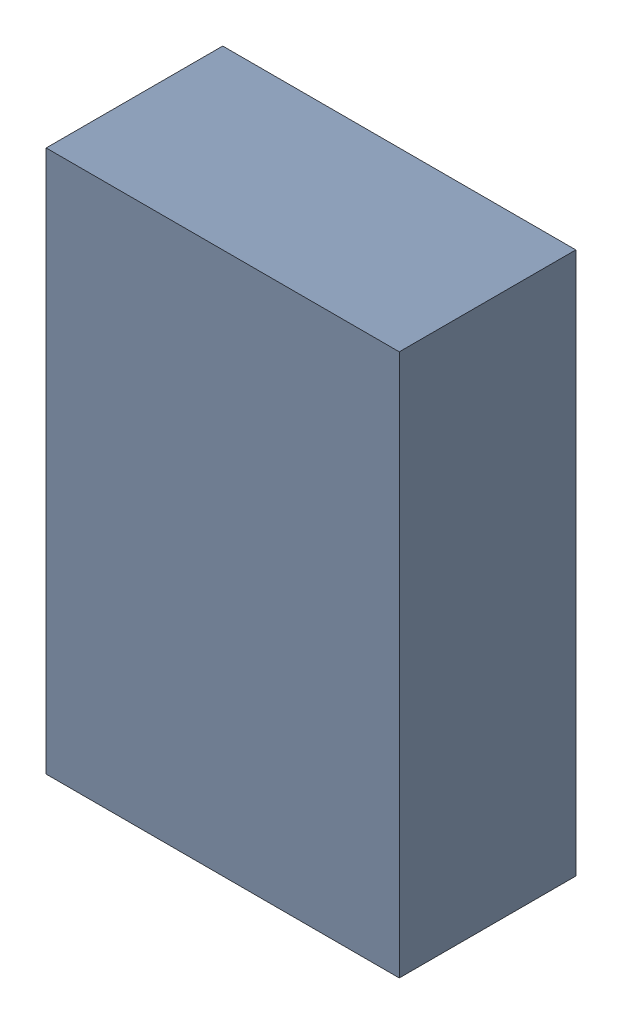
SolidWorks assembly R6-1, configuration Default. Lengths in mm.
Overall size (1.4 2.15 0.7).
2 component instances, 1 part files, 0 mates.
Components (placement in the parent):
- 959208120-1-1: 959208120-1 [Default] at (122.9827 82.385 0) size (1.4 2.15 0.7)
  - Extruded-51-1: Extruded-51 [Default] at origin size (1.4 2.15 0.7)
